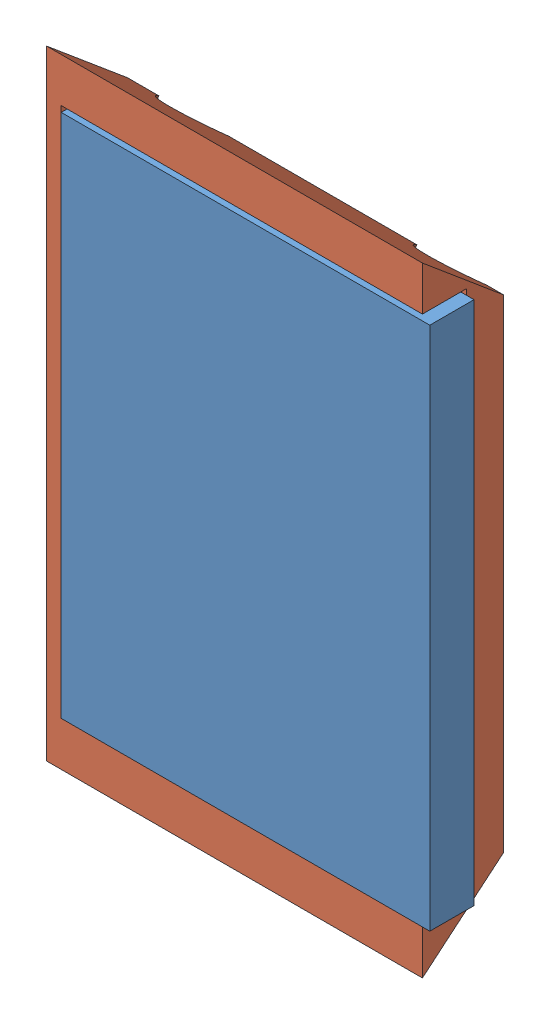
SolidWorks assembly assembly_holder_mirror_20200806, configuration Default. Lengths in mm.
Overall size (26 42 11.5).
7 component instances, 3 part files, 6 mates.
Components (placement in the parent):
- mirror_20200728-1: mirror_20200728 [Default] at (-0.8752 0.694 26.7611) size (25 35.6 3)
- holder_mirror_20200806-1: holder_mirror_20200806 [Default] at (11.1248 18.694 29.7611) x (1 0 0) z (0 1 0) size (25.5 11.5 42)
- HXN3_1_20200728-1: HXN3_1_20200728 [Default] at (19.7088 33.7505 26.7611) x (0 0 -1) z (1 0 0) size (1 3 3)
- HXN3_1_20200728-2: HXN3_1_20200728 [Default] at (19.9633 3.4538 25.7611) x (0 0 1) z (-1 0 0) size (1 3 3)
- HXN3_1_20200728-3: HXN3_1_20200728 [Default] at (2.2578 33.8394 25.7611) x (0 0 1) z (-1 0 0) size (1 3 3)
- HXN3_1_20200728-4: HXN3_1_20200728 [Default] at (2.385 3.816 25.7611) x (0 0 1) z (-1 0 0) size (1 3 3)
- HXN3_1_20200728-5: HXN3_1_20200728 [Default] at (-1.5599 18.6296 21.3482) size (1 3 3)
Mates (geometry in assembly coordinates):
- Coincident5: coincident aligned: line of mirror_20200728-1 through (-0.8752 0.694 26.7611) axis (1 0 0); line of holder_mirror_20200806-1 through (-0.8752 0.694 26.7611) axis (1 0 0)
- Coincident6: coincident aligned: line of mirror_20200728-1 through (-0.8752 36.294 26.7611) axis (0 -1 0); line of holder_mirror_20200806-1 through (-0.8752 36.694 26.7611) axis (0 -1 0)
- Coincident7: coincident anti-aligned: plane of mirror_20200728-1 through (-0.8752 0.694 26.7611) normal (0 0 -1); plane of HXN3_1_20200728-1 through (19.7088 33.7505 26.7611) normal (0 0 1)
- Coincident8: coincident anti-aligned: plane of mirror_20200728-1 through (-0.8752 0.694 26.7611) normal (0 0 -1); plane of HXN3_1_20200728-3 through (2.2578 35.2894 26.7611) normal (0 0 1)
- Coincident9: coincident anti-aligned: plane of mirror_20200728-1 through (-0.8752 0.694 26.7611) normal (0 0 -1); plane of HXN3_1_20200728-4 through (2.385 5.266 26.7611) normal (0 0 1)
- Coincident10: coincident anti-aligned: plane of mirror_20200728-1 through (-0.8752 0.694 26.7611) normal (0 0 -1); plane of HXN3_1_20200728-2 through (19.9633 4.9038 26.7611) normal (0 0 1)
